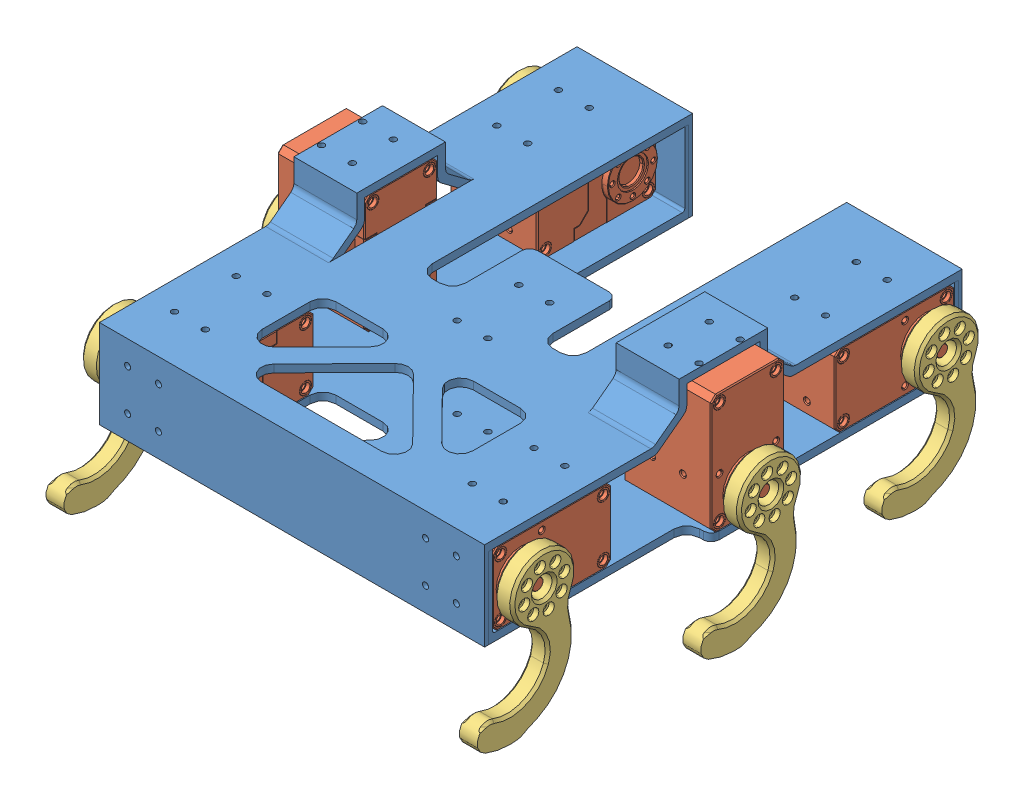
SolidWorks assembly 0100-A-Drive Base, configuration Default. Lengths in mm.
Overall size (187.75 93.38 257.5).
13 component instances, 3 part files, 13 mates.
Components (placement in the parent):
- 0100-P-01-Unibody Frame-2: 0100-P-01-Unibody Frame [Default] at origin size (178 52.5 257.5)
- DYNAMIXEL XM,H-430-1: DYNAMIXEL XM,H-430 [Default] at (58 14.25 -78.75) x (0 -1 0) z (1 0 0) size (28.5 46.5 42.4)
- DYNAMIXEL XM,H-430-2: DYNAMIXEL XM,H-430 [Default] at (58 14.25 78.75) x (0 1 0) z (1 0 0) size (28.5 46.5 42.4)
- 0100-P-02-Leg-2: 0100-P-02-Leg [Default] at (77 14.25 78.75) x (1 0 0) z (0 0.538369 0.842709) size (7.78 62.2 37.5)
- DYNAMIXEL XM,H-430-3: DYNAMIXEL XM,H-430 [Default] at (67.5 11.25 0) x (0 0 1) z (1 0 0) size (28.5 46.5 42.4)
- 0100-P-02-Leg-3: 0100-P-02-Leg [Default] at (86.5 11.25 0) x (1 0 0) z (0 0.56477 0.825248) size (7.78 62.2 37.5)
- DYNAMIXEL XM,H-430-4: DYNAMIXEL XM,H-430 [Default] at (-58 14.25 -78.75) x (0 1 0) z (-1 0 0) size (28.5 46.5 42.4)
- DYNAMIXEL XM,H-430-5: DYNAMIXEL XM,H-430 [Default] at (-58 14.25 78.75) x (0 -1 0) z (-1 0 0) size (28.5 46.5 42.4)
- 0100-P-02-Leg-4: 0100-P-02-Leg [Default] at (-93.477 11.25 0) x (1 0 0) z (0 0.56477 0.825248) size (7.78 62.2 37.5)
- DYNAMIXEL XM,H-430-6: DYNAMIXEL XM,H-430 [Default] at (-67.5 11.25 0) x (0 0 -1) z (-1 0 0) size (28.5 46.5 42.4)
- 0100-P-02-Leg-5: 0100-P-02-Leg [Default] at (-83.977 14.25 78.75) x (1 0 0) z (0 0.538369 0.842709) size (7.78 62.2 37.5)
- 0100-P-02-Leg-8: 0100-P-02-Leg [Default] at (77 14.25 -78.75) x (1 0 0) z (0 0.538369 0.842709) size (7.78 62.2 37.5)
- 0100-P-02-Leg-9: 0100-P-02-Leg [Default] at (-83.977 14.25 -78.75) x (1 0 0) z (0 0.538369 0.842709) size (7.78 62.2 37.5)
Mates (geometry in assembly coordinates):
- Coincident4: coincident anti-aligned: plane of DYNAMIXEL XM,H-430-1 through (41 0 -43.5) normal (0 -1 0)
- Concentric2: concentric aligned: cylinder of 0100-P-02-Leg-2 through (84 14.25 78.75) axis (-1 0 0) radius 4.05; cylinder of DYNAMIXEL XM,H-430-2 through (79.35 14.25 78.75) axis (-1 0 0) radius 4
- Coincident7: coincident anti-aligned: plane of DYNAMIXEL XM,H-430-2 through (77 14.25 78.75) normal (1 0 0); plane of 0100-P-02-Leg-2 through (77 14.25 78.75) normal (-1 0 0)
- Coincident10: coincident: line of 0100-P-01-Unibody Frame-2 through (75 0 -90) axis (0 0 1); plane of DYNAMIXEL XM,H-430-1 through (75 14.25 -78.75) normal (1 0 0)
- Coincident11: coincident anti-aligned: plane of DYNAMIXEL XM,H-430-3 through (50.5 0 14.25) normal (0 -1 0)
- Coincident12: coincident: line of 0100-P-01-Unibody Frame-2 through (84.5 0 -14.25) axis (0 0 1); plane of DYNAMIXEL XM,H-430-3 through (84.5 11.25 0) normal (1 0 0)
- Coincident13: coincident aligned: plane of DYNAMIXEL XM,H-430-3 through (67.5 11.25 0) normal (0 0 1)
- Concentric3: concentric aligned: cylinder of DYNAMIXEL XM,H-430-3 through (88.85 11.25 0) axis (-1 0 0) radius 4; cylinder of 0100-P-02-Leg-3 through (93.5 11.25 0) axis (-1 0 0) radius 4.05
- Coincident14: coincident anti-aligned: plane of DYNAMIXEL XM,H-430-3 through (86.5 11.25 0) normal (1 0 0); plane of 0100-P-02-Leg-3 through (86.5 11.25 0) normal (-1 0 0)
- Coincident15: coincident: line of 0100-P-01-Unibody Frame-2 through (75 0 -90) axis (-1 0 0); plane of DYNAMIXEL XM,H-430-1 through (41 0 -90) normal (0 0 -1)
- Coincident16: coincident: line of 0100-P-01-Unibody Frame-2 through (75 0 -90) axis (0 0 1); plane of DYNAMIXEL XM,H-430-1 through (75 14.25 -78.75) normal (1 0 0)
- Concentric6: concentric anti-aligned: cylinder of DYNAMIXEL XM,H-430-1 through (78.9 14.25 -78.75) axis (1 0 0) radius 2.25; cylinder of 0100-P-02-Leg-8 through (84 14.25 -78.75) axis (-1 0 0) radius 4.05
- Coincident19: coincident anti-aligned: plane of DYNAMIXEL XM,H-430-1 through (77 14.25 -78.75) normal (1 0 0); plane of 0100-P-02-Leg-8 through (77 14.25 -78.75) normal (-1 0 0)
